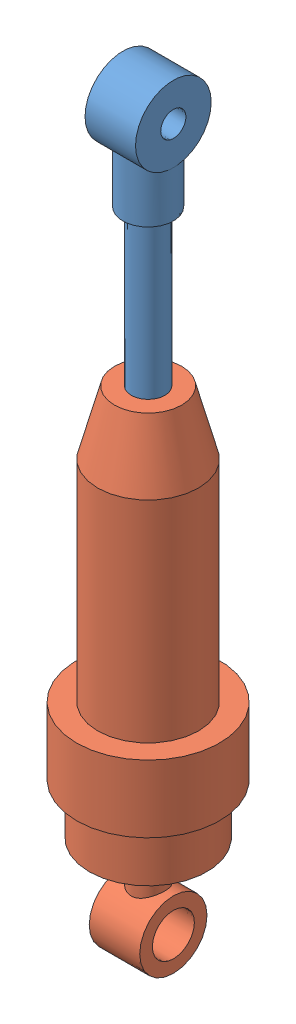
SolidWorks assembly 避震器简化, configuration 默认. Lengths in mm.
Overall size (17 91.94 17).
2 component instances, 2 part files, 3 mates.
Components (placement in the parent):
- 避震器简化-1: 避震器简化 [默认] at (-13.0596 2.9126 7.6433) size (6 39.5 9)
- 避震器下简化-1: 避震器下简化 [默认] at (-13.0596 4.4718 7.6433) size (17 59 17)
Mates (geometry in assembly coordinates):
- 同心1: concentric anti-aligned: circle of 避震器简化-1; circle of 避震器下简化-1
- 平行1: parallel aligned: plane of 避震器简化-1 through (-16.0596 22.9126 7.6433) normal (-1 0 0); plane of 避震器下简化-1 through (-16.0596 -60.5282 7.6433) normal (-1 0 0)
- LimitDistance3: limit distance = 18.4409 mm anti-aligned: plane of 避震器下简化-1 through (-13.0596 -5.5282 7.6433) normal (0 1 0); plane of 避震器简化-1 through (-13.0596 12.9126 7.6433) normal (0 -1 0)
